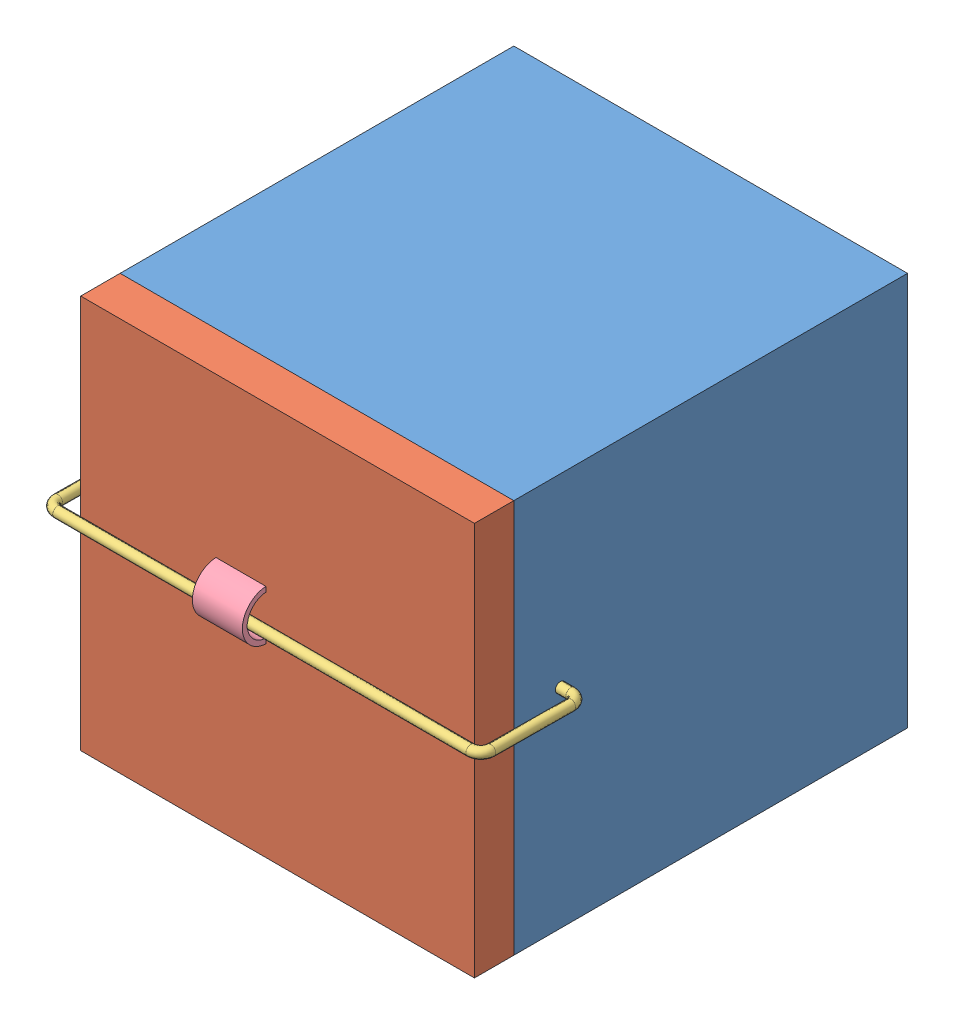
SolidWorks assembly Retainment ASM, configuration Default. Lengths in mm.
Overall size (112.54 100 115.98).
4 component instances, 4 part files, 6 mates.
Components (placement in the parent):
- CubeSat-1: CubeSat [Default] at (19.4602 82.0864 65.8726) size (100 100 100)
- Deployable-1: Deployable [Default] at (19.4602 82.0864 165.8726) size (100 100 10)
- Fishing Line-3: Fishing Line [Default] at (19.6589 85.1321 154.0624) x (1 0 0) z (0 -0.008727 -0.999962) size (112.54 2.54 27.94)
- Nichrome Wire-1: Nichrome Wire [Default] at (3.8018 79.0789 162.8063) x (0 1 0) z (1 0 0) size (12.7 19.05 12.7)
Mates (geometry in assembly coordinates):
- Coincident1: coincident aligned: line of CubeSat-1 through (69.4602 132.0864 165.8726) axis (-1 0 0); line of Deployable-1 through (69.4602 132.0864 165.8726) axis (-1 0 0)
- Coincident2: coincident aligned: plane of CubeSat-1 through (69.4602 32.0864 165.8726) normal (1 0 0); plane of Deployable-1 through (69.4602 32.0864 175.8726) normal (1 0 0)
- LimitAngle1: limit planar angle = 0 rad anti-aligned: plane of Deployable-1 through (19.4602 82.0864 165.8726) normal (0 0 -1); plane of CubeSat-1 through (19.4602 82.0864 165.8726) normal (0 0 1)
- Parallel1: parallel anti-aligned: plane of CubeSat-1 through (-30.5398 32.0864 165.8726) normal (-1 0 0); plane of Fishing Line-3 through (-22.6411 85.1321 154.0624) normal (1 0 0)
- Parallel2: parallel anti-aligned: plane of Deployable-1; plane of Nichrome Wire-1 through (16.5018 91.7789 162.8063) normal (0 0 -1)
- Parallel3: parallel anti-aligned: plane of CubeSat-1 through (-30.5398 32.0864 165.8726) normal (-1 0 0); plane of Nichrome Wire-1 through (16.5018 85.4289 175.5063) normal (1 0 0)
